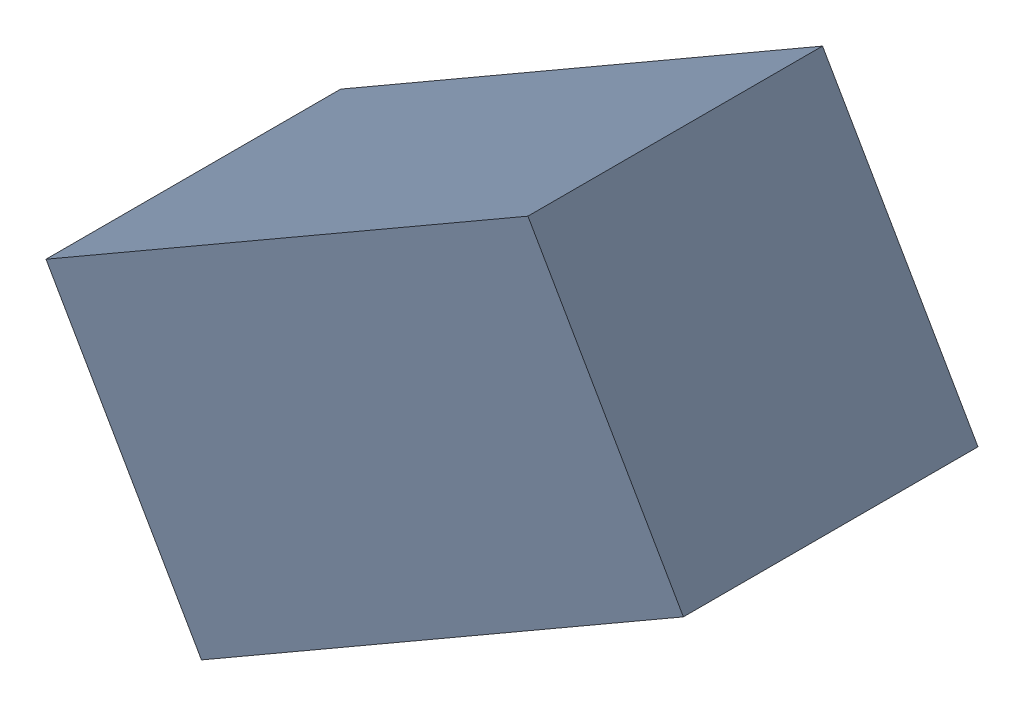
SolidWorks assembly R2_TDA5, configuration Standard. Lengths in mm.
Overall size (1.95 1.67 0.9).
2 component instances, 1 part files, 0 mates.
Components (placement in the parent):
- 885544008-1: 885544008 [Standard] at (-41.8269 -34.1296 0) size (1.95 1.67 0.9)
  - Extruded_15-1: Extruded_15 [Standard] at origin size (1.95 1.67 0.9)
